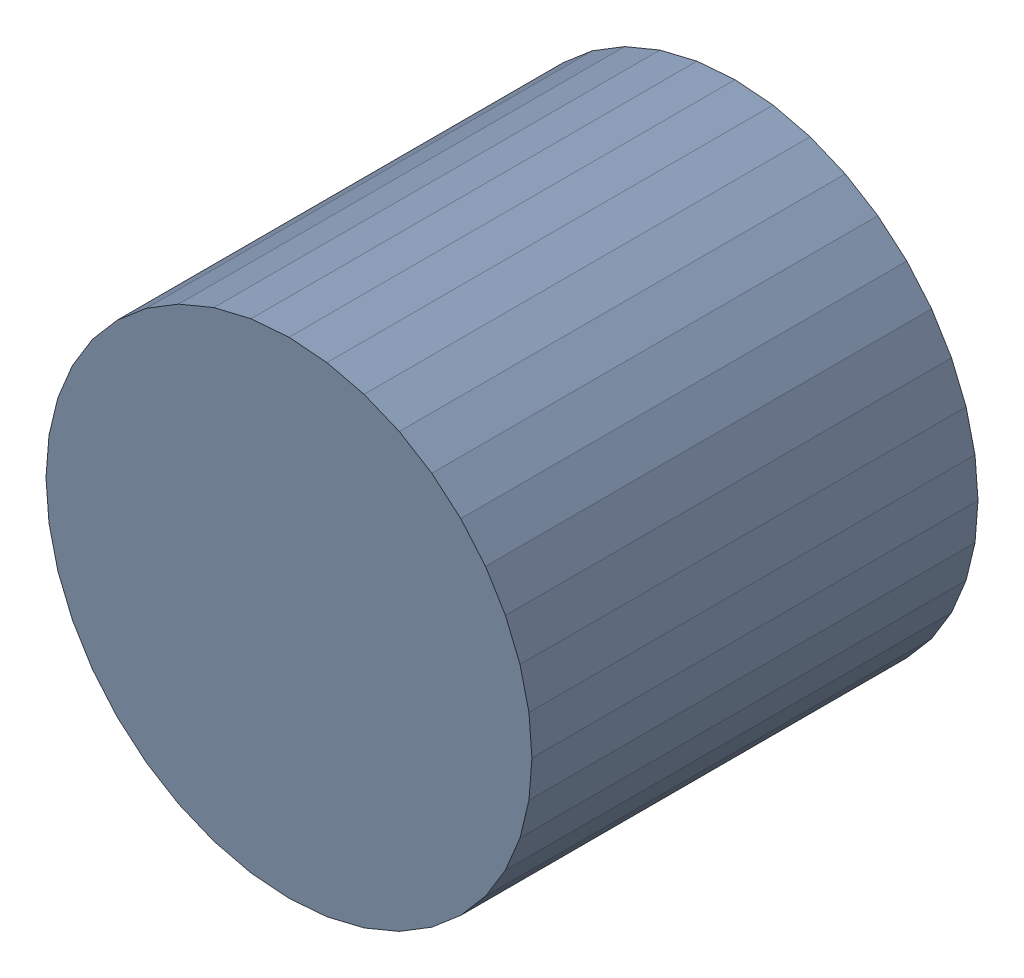
SolidWorks assembly CoutB1Kanaloa_v2.0.0_Power, configuration Default. Lengths in mm.
Overall size (6.32 6.32 5.8).
2 component instances, 1 part files, 0 mates.
Components (placement in the parent):
- 352892112-1: 352892112 [Default] at (62.025 46 0) size (6.32 6.32 5.8)
  - Extruded_11-1: Extruded_11 [Default] at origin size (6.32 6.32 5.8)
